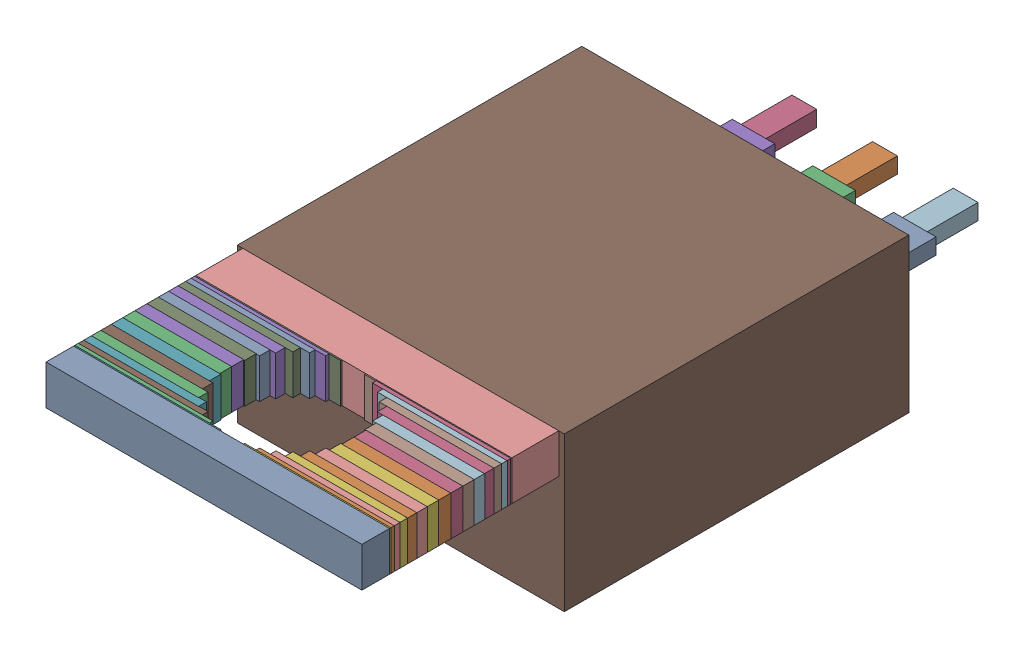
SolidWorks assembly Q4.step, configuration Default. Lengths in mm.
Overall size (10.3 4.85 21.45).
82 component instances, 18 part files, 0 mates.
Components (placement in the parent):
- 6138241504.step-1: 6138241504.step [Default] at (62.357 33.033 18.98) size (9.95 1.25 0.87)
  - Extruded-25.step-1: Extruded-25.step [Default] at origin size (9.95 1.25 0.87)
- 6138241344.step-1: 6138241344.step [Default] at (65.807 33.033 17.05) size (3.05 1.25 0.38)
  - Extruded-26.step-1: Extruded-26.step [Default] at origin size (3.05 1.25 0.38)
- 6138241344.step-2: 6138241344.step [Default] at (58.907 33.033 17.05) size (3.05 1.25 0.38)
  - Extruded-26.step-1: Extruded-26.step [Default] at origin size (3.05 1.25 0.38)
- 6138241104.step-1: 6138241104.step [Default] at (65.807 33.033 16.67) size (3.05 1.25 0.38)
  - Extruded-27.step-1: Extruded-27.step [Default] at origin size (3.05 1.25 0.38)
- 6138241104.step-2: 6138241104.step [Default] at (58.907 33.033 16.67) size (3.05 1.25 0.38)
  - Extruded-27.step-1: Extruded-27.step [Default] at origin size (3.05 1.25 0.38)
- 6138240864.step-1: 6138240864.step [Default] at (65.7885 33.033 17.43) size (3.09 1.25 0.36)
  - Extruded-28.step-1: Extruded-28.step [Default] at origin size (3.09 1.25 0.36)
- 6138240864.step-2: 6138240864.step [Default] at (58.9255 33.033 17.43) size (3.09 1.25 0.36)
  - Extruded-28.step-1: Extruded-28.step [Default] at origin size (3.09 1.25 0.36)
- 6138240624.step-1: 6138240624.step [Default] at (65.7885 33.033 16.31) size (3.09 1.25 0.37)
  - Extruded-29.step-1: Extruded-29.step [Default] at origin size (3.09 1.25 0.37)
- 6138240624.step-2: 6138240624.step [Default] at (58.9255 33.033 16.31) size (3.09 1.25 0.37)
  - Extruded-29.step-1: Extruded-29.step [Default] at origin size (3.09 1.25 0.37)
- 6138240384.step-1: 6138240384.step [Default] at (65.7337 33.033 17.79) size (3.2 1.25 0.33)
  - Extruded-30.step-1: Extruded-30.step [Default] at origin size (3.2 1.25 0.33)
- 6138240384.step-2: 6138240384.step [Default] at (58.9803 33.033 17.79) size (3.2 1.25 0.33)
  - Extruded-30.step-1: Extruded-30.step [Default] at origin size (3.2 1.25 0.33)
- 6138240144.step-1: 6138240144.step [Default] at (65.7337 33.033 15.98) size (3.2 1.25 0.34)
  - Extruded-31.step-1: Extruded-31.step [Default] at origin size (3.2 1.25 0.34)
- 6138240144.step-2: 6138240144.step [Default] at (58.9803 33.033 15.98) size (3.2 1.25 0.34)
  - Extruded-31.step-1: Extruded-31.step [Default] at origin size (3.2 1.25 0.34)
- 6138239904.step-1: 6138239904.step [Default] at (65.6448 33.033 18.12) size (3.37 1.25 0.3)
  - Extruded-32.step-1: Extruded-32.step [Default] at origin size (3.37 1.25 0.3)
- 6138239904.step-2: 6138239904.step [Default] at (59.0692 33.033 18.12) size (3.37 1.25 0.3)
  - Extruded-32.step-1: Extruded-32.step [Default] at origin size (3.37 1.25 0.3)
- 6138239904.step-3: 6138239904.step [Default] at (65.6448 33.033 15.69) size (3.37 1.25 0.3)
  - Extruded-32.step-1: Extruded-32.step [Default] at origin size (3.37 1.25 0.3)
- 6138239904.step-4: 6138239904.step [Default] at (59.0692 33.033 15.69) size (3.37 1.25 0.3)
  - Extruded-32.step-1: Extruded-32.step [Default] at origin size (3.37 1.25 0.3)
- 6138239504.step-1: 6138239504.step [Default] at (65.5251 33.033 18.41) size (3.61 1.25 0.25)
  - Extruded-33.step-1: Extruded-33.step [Default] at origin size (3.61 1.25 0.25)
- 6138239504.step-2: 6138239504.step [Default] at (59.1889 33.033 18.41) size (3.61 1.25 0.25)
  - Extruded-33.step-1: Extruded-33.step [Default] at origin size (3.61 1.25 0.25)
- 6138239264.step-1: 6138239264.step [Default] at (65.5251 33.033 15.45) size (3.61 1.25 0.24)
  - Extruded-34.step-1: Extruded-34.step [Default] at origin size (3.61 1.25 0.24)
- 6138239264.step-2: 6138239264.step [Default] at (59.1889 33.033 15.45) size (3.61 1.25 0.24)
  - Extruded-34.step-1: Extruded-34.step [Default] at origin size (3.61 1.25 0.24)
- 6138239024.step-1: 6138239024.step [Default] at (65.3792 33.033 18.65) size (3.91 1.25 0.18)
  - Extruded-35.step-1: Extruded-35.step [Default] at origin size (3.91 1.25 0.18)
- 6138239024.step-2: 6138239024.step [Default] at (59.3348 33.033 18.65) size (3.91 1.25 0.18)
  - Extruded-35.step-1: Extruded-35.step [Default] at origin size (3.91 1.25 0.18)
- 6138239024.step-3: 6138239024.step [Default] at (65.3792 33.033 15.27) size (3.91 1.25 0.18)
  - Extruded-35.step-1: Extruded-35.step [Default] at origin size (3.91 1.25 0.18)
- 6138239024.step-4: 6138239024.step [Default] at (59.3348 33.033 15.27) size (3.91 1.25 0.18)
  - Extruded-35.step-1: Extruded-35.step [Default] at origin size (3.91 1.25 0.18)
- 6138238624.step-1: 6138238624.step [Default] at (65.2128 33.033 18.83) size (4.24 1.25 0.11)
  - Extruded-36.step-1: Extruded-36.step [Default] at origin size (4.24 1.25 0.11)
- 6138238624.step-2: 6138238624.step [Default] at (59.5012 33.033 18.83) size (4.24 1.25 0.11)
  - Extruded-36.step-1: Extruded-36.step [Default] at origin size (4.24 1.25 0.11)
- 6138238384.step-1: 6138238384.step [Default] at (65.2128 33.033 15.16) size (4.24 1.25 0.12)
  - Extruded-37.step-1: Extruded-37.step [Default] at origin size (4.24 1.25 0.12)
- 6138238384.step-2: 6138238384.step [Default] at (59.5012 33.033 15.16) size (4.24 1.25 0.12)
  - Extruded-37.step-1: Extruded-37.step [Default] at origin size (4.24 1.25 0.12)
- 6138238144.step-1: 6138238144.step [Default] at (65.0323 33.033 18.94) size (4.6 1.25 0.04)
  - Extruded-38.step-1: Extruded-38.step [Default] at origin size (4.6 1.25 0.04)
- 6138238144.step-2: 6138238144.step [Default] at (59.6817 33.033 18.94) size (4.6 1.25 0.04)
  - Extruded-38.step-1: Extruded-38.step [Default] at origin size (4.6 1.25 0.04)
- 6138238144.step-3: 6138238144.step [Default] at (65.0323 33.033 15.13) size (4.6 1.25 0.04)
  - Extruded-38.step-1: Extruded-38.step [Default] at origin size (4.6 1.25 0.04)
- 6138238144.step-4: 6138238144.step [Default] at (59.6817 33.033 15.13) size (4.6 1.25 0.04)
  - Extruded-38.step-1: Extruded-38.step [Default] at origin size (4.6 1.25 0.04)
- 6138237744.step-1: 6138237744.step [Default] at (62.357 33.033 13.65) size (9.95 1.25 1.48)
  - Extruded-39.step-1: Extruded-39.step [Default] at origin size (9.95 1.25 1.48)
- 6138237584.step-1: 6138237584.step [Default] at (62.357 31.233 2.8) size (10.3 4.85 10.85)
  - Extruded-40.step-1: Extruded-40.step [Default] at origin size (10.3 4.85 10.85)
- 6138237424.step-1: 6138237424.step [Default] at (64.897 30.988 -1.6) size (0.78 0.5 1.6)
  - Extruded-41.step-1: Extruded-41.step [Default] at origin size (0.78 0.5 1.6)
- 6138237264.step-1: 6138237264.step [Default] at (64.897 30.988 0) size (1.34 0.5 2.8)
  - Extruded-42.step-1: Extruded-42.step [Default] at origin size (1.34 0.5 2.8)
- 6138237424.step-2: 6138237424.step [Default] at (62.357 30.988 -1.6) size (0.78 0.5 1.6)
  - Extruded-41.step-1: Extruded-41.step [Default] at origin size (0.78 0.5 1.6)
- 6138237264.step-2: 6138237264.step [Default] at (62.357 30.988 0) size (1.34 0.5 2.8)
  - Extruded-42.step-1: Extruded-42.step [Default] at origin size (1.34 0.5 2.8)
- 6138237424.step-3: 6138237424.step [Default] at (59.817 30.988 -1.6) size (0.78 0.5 1.6)
  - Extruded-41.step-1: Extruded-41.step [Default] at origin size (0.78 0.5 1.6)
- 6138237264.step-3: 6138237264.step [Default] at (59.817 30.988 0) size (1.34 0.5 2.8)
  - Extruded-42.step-1: Extruded-42.step [Default] at origin size (1.34 0.5 2.8)
